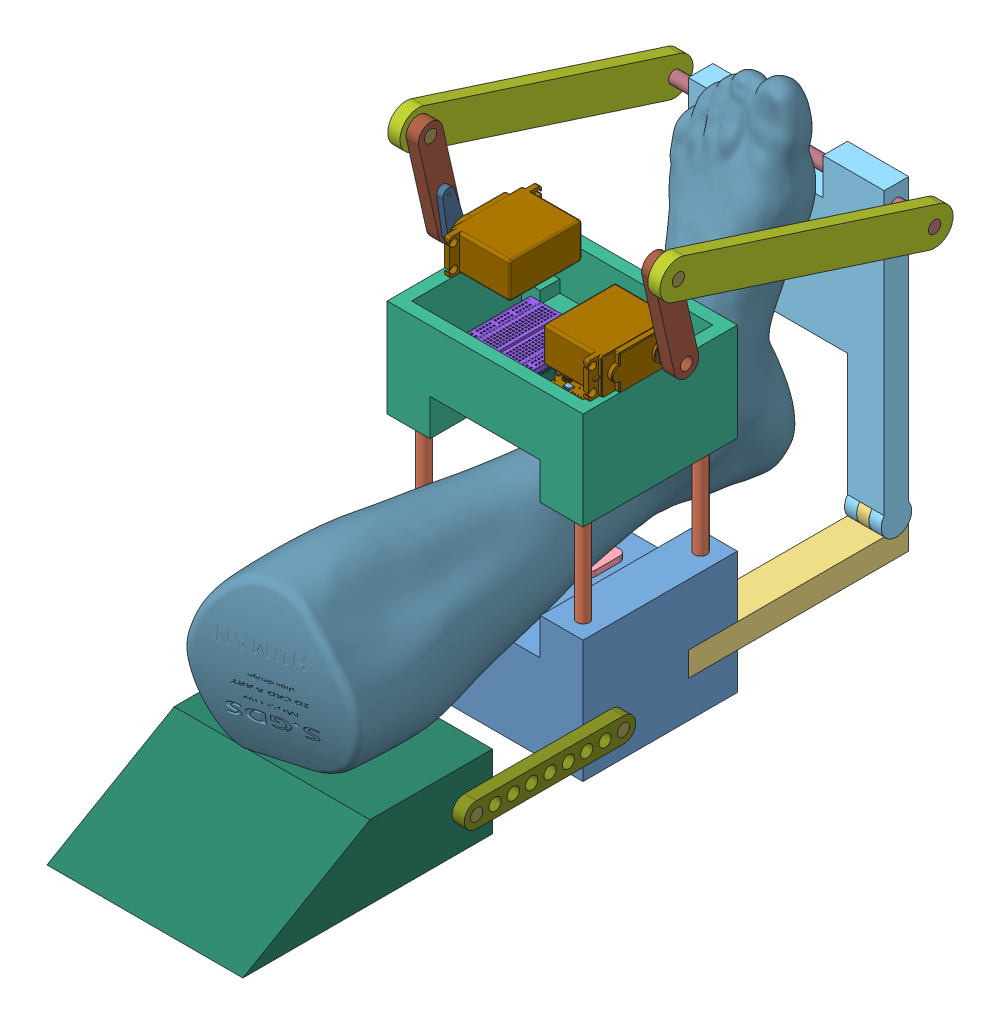
SolidWorks assembly Design104, configuration Default. Lengths in mm.
Overall size (222.4 366.53 552.81).
78 component instances, 34 part files, 73 mates.
Components (placement in the parent):
- Base-1: Base [Default] at (54.0688 54.3707 145.5855) size (160 100 126)
- AdjustmentScrew-1: AdjustmentScrew [Default] at (-10.9312 64.3707 130.5855) x (-0.217507 0 -0.976059) z (0 -1 0) size (10 10 160)
- AdjustmentScrew-2: AdjustmentScrew [Default] at (119.0688 64.3707 130.5855) x (1 0 0) z (0 -1 0) size (10 10 160)
- AdjustmentScrew-3: AdjustmentScrew [Default] at (119.0688 64.3707 34.5855) x (1 0 0) z (0 -1 0) size (10 10 160)
- AdjustmentScrew-4: AdjustmentScrew [Default] at (-10.9312 64.3707 34.5855) x (1 0 0) z (0 -1 0) size (10 10 160)
- ExtensionBase-1: ExtensionBase [Default] at (134.0688 34.3707 59.5855) size (30 40 182.5)
- ExtensionBase-2: ExtensionBase [Default] at (4.0688 34.3707 59.5855) size (30 40 182.5)
- Sensor-1: Sensor [Default] at (54.0688 78.9052 55.5855) size (20 10 30)
- Sensor-2: Sensor [Default] at (54.0688 78.1824 109.5855) size (20 10 30)
- FootBase-1: FootBase [Default] at (54.0688 184.3707 -100.4145) size (160 250 25)
- TopBox-2: TopBox [Default] at (54.0688 224.3707 145.5855) size (160 80 126)
- Connector-3: Connector [Default] at (-57.1312 318.1914 -5.7428) x (1 0 0) z (0 0.307461 0.951561) size (10 30 250)
- Connector-4: Connector [Default] at (165.2688 318.1914 -5.7428) x (-1 0 0) z (0 0.307461 0.951561) size (10 30 250)
- proto_400-2: proto_400 [Default] at (26.0688 224.3707 94.5855) x (1 0 0) z (0 1 0) size (55.3 83.3 10.01)
- Assembly Arduino Uno R3-2: Assembly Arduino Uno R3 [Default] at (52.5044 167.9903 76.8718) x (0 0 1) z (0 1 0) size (75 53.3 16.1)
  - Assembly Arduino Uno R3.STEP-1: Assembly Arduino Uno R3.STEP [Default] at origin size (75 53.3 16.1)
    - 1. Arduino uno PCB.STEP-1: 1. Arduino uno PCB.STEP [Default] at (23.1768 3.2644 56.3804) size (68.53 53.3 1.6)
    - 2. USB.STEP-1: 2. USB.STEP [Default] at (-0.091 39.0544 63.5804) x (0 -1 0) z (-1 0 0) size (14.95 14.22 16.6)
    - 12. Button arduino.STEP-1: 12. Button arduino.STEP [Default] at (-16.3125 58.8663 57.9804) size (8.4 6.2 3)
    - 3. dc jack arduino.STEP-1: 3. dc jack arduino.STEP [Default] at (-15.671 11.3644 63.4804) x (0 1 0) z (1 0 0) size (9.8 16.1 14.4)
    - 4. atmega 328p.STEP-1: 4. atmega 328p.STEP [Default] at (32.929 30.6944 58.7304) x (-1 0 0) z (0 0 -1) size (8.99 8.99 1.2)
    - 2.0  header female 6.STEP-1: 2.0  header female 6.STEP [Default] at (52.3937 64.9176 37.8614) x (0 1 0) z (1 0 0) size (2.54 11.7 15.24)
    - 2.0  header female 8.STEP-1: 2.0  header female 8.STEP [Default] at (34.6337 64.9176 37.8614) x (0 1 0) z (1 0 0) size (2.54 11.7 20.32)
    - 2.0  header female 10.STEP-1: 2.0  header female 10.STEP [Default] at (30.799 113.1576 37.8614) x (0 1 0) z (1 0 0) size (2.54 11.7 25.4)
    - 2.0  header female 8.STEP-2: 2.0  header female 8.STEP [Default] at (52.3946 113.1576 37.8614) x (0 1 0) z (1 0 0) size (2.54 11.7 20.32)
    - 5. header male.STEP-1: 5. header male.STEP [Default] at (56.3437 33.5885 57.9804) x (0 1 0) z (0 0 1) size (7.62 5.08 12.7)
    - 10. cap arduino.STEP-1: 10. cap arduino.STEP [Default] at (12.0737 13.0344 59.9804) x (-1 0 0) z (0 0 -1) size (6 5.3 6.2)
    - 10. cap arduino.STEP-2: 10. cap arduino.STEP [Default] at (4.579 13.0344 59.9804) x (-1 0 0) z (0 0 -1) size (6 5.3 6.2)
    - 8. Arduino part 16MHZ.STEP-1: 8. Arduino part 16MHZ.STEP [Default] at (14.849 43.7344 57.9804) size (13.58 4.8 3.85)
    - 8. Arduino part 16MHZ.STEP-2: 8. Arduino part 16MHZ.STEP [Default] at (41.3137 38.6244 57.9804) x (0 1 0) z (0 0 1) size (13.58 4.8 3.85)
    - 6. diode.STEP-1: 6. diode.STEP [Default] at (11.139 5.7644 59.1804) x (0 1 0) z (0 0 1) size (3.11 5.3 2.43)
    - 13. LM1117.STEP-1: 13. LM1117.STEP [Default] at (-16.299 58.867 57.8807) size (7.32 6.7 1.7)
    - 14. Micro chip part Arduino.STEP-1: 14. Micro chip part Arduino.STEP [Default] at (-16.306 58.8741 57.9804) size (9.9 6 1.75)
    - 7.Lm358 arduino.STEP-1: 7.Lm358 arduino.STEP [Default] at (17.789 18.7444 58.8704) size (6 4.9 1.75)
    - 11. Transistor.STEP-1: 11. Transistor.STEP [Default] at (-16.3121 58.8727 57.9804) size (2.34 2.92 1)
    - 11. Transistor.STEP-2: 11. Transistor.STEP [Default] at (-4.1821 48.9727 57.9804) size (2.34 2.92 1)
    - 9. part.STEP-1: 9. part.STEP [Default] at (19.109 45.7244 58.3804) x (1 0 0) z (0 1 0) size (1.05 0.4 0.55)
    - 9. part.STEP-2: 9. part.STEP [Default] at (19.109 43.3944 58.3804) x (1 0 0) z (0 1 0) size (1.05 0.4 0.55)
    - 9. part.STEP-3: 9. part.STEP [Default] at (19.109 40.6944 58.3804) x (1 0 0) z (0 1 0) size (1.05 0.4 0.55)
    - 9. part.STEP-4: 9. part.STEP [Default] at (19.109 37.9944 58.3804) x (1 0 0) z (0 1 0) size (1.05 0.4 0.55)
    - 9. part.STEP-5: 9. part.STEP [Default] at (19.109 33.0944 58.3804) x (1 0 0) z (0 1 0) size (1.05 0.4 0.55)
    - 9. part.STEP-6: 9. part.STEP [Default] at (19.109 35.4244 58.3804) x (1 0 0) z (0 1 0) size (1.05 0.4 0.55)
    - 9. part.STEP-7: 9. part.STEP [Default] at (19.109 30.4244 58.3804) x (1 0 0) z (0 1 0) size (1.05 0.4 0.55)
    - 9. part.STEP-8: 9. part.STEP [Default] at (19.109 28.1244 58.3804) x (1 0 0) z (0 1 0) size (1.05 0.4 0.55)
    - 9. part.STEP-9: 9. part.STEP [Default] at (19.109 25.7244 58.3804) x (1 0 0) z (0 1 0) size (1.05 0.4 0.55)
    - 9. part.STEP-10: 9. part.STEP [Default] at (19.109 23.4244 58.3804) x (1 0 0) z (0 1 0) size (1.05 0.4 0.55)
    - 15. part 1.STEP-1: 15. part 1.STEP [Default] at (49.8188 35.6465 58.9804) x (0 -1 0) z (1 0 0) size (2.62 1 1.38)
    - 9. part.STEP-11: 9. part.STEP [Default] at (48.0248 40.4298 57.9804) x (0 -1 0) z (-1 0 0) size (1.05 0.4 0.55)
    - 9. part.STEP-12: 9. part.STEP [Default] at (48.0248 36.0298 57.9804) x (0 -1 0) z (-1 0 0) size (1.05 0.4 0.55)
    - 9. part.STEP-13: 9. part.STEP [Default] at (48.0248 31.6298 57.9804) x (0 -1 0) z (-1 0 0) size (1.05 0.4 0.55)
    - 9. part.STEP-14: 9. part.STEP [Default] at (4.3842 45.5109 58.3804) x (1 0 0) z (0 1 0) size (1.05 0.4 0.55)
    - 9. part.STEP-15: 9. part.STEP [Default] at (8.4842 45.5109 58.3804) x (1 0 0) z (0 1 0) size (1.05 0.4 0.55)
    - 9. part.STEP-16: 9. part.STEP [Default] at (12.5842 45.5109 58.3804) x (1 0 0) z (0 1 0) size (1.05 0.4 0.55)
    - 9. part.STEP-17: 9. part.STEP [Default] at (-1.7801 31.2518 58.3804) x (1 0 0) z (0 1 0) size (1.05 0.4 0.55)
    - 9. part.STEP-18: 9. part.STEP [Default] at (-1.7801 28.9518 58.3804) x (1 0 0) z (0 1 0) size (1.05 0.4 0.55)
    - 9. part.STEP-19: 9. part.STEP [Default] at (7.5312 23.47 58.3804) x (1 0 0) z (0 1 0) size (1.05 0.4 0.55)
    - 9. part.STEP-20: 9. part.STEP [Default] at (13.1312 23.47 58.3804) x (1 0 0) z (0 1 0) size (1.05 0.4 0.55)
    - 9. part.STEP-21: 9. part.STEP [Default] at (-0.9044 25.5823 58.3804) x (0 1 0) z (-1 0 0) size (1.05 0.4 0.55)
    - 9. part.STEP-22: 9. part.STEP [Default] at (1.7956 25.5823 58.3804) x (0 1 0) z (-1 0 0) size (1.05 0.4 0.55)
    - 9. part.STEP-23: 9. part.STEP [Default] at (2.1347 17.489 58.3804) x (0 1 0) z (-1 0 0) size (1.05 0.4 0.55)
    - 9. part.STEP-24: 9. part.STEP [Default] at (9.5347 17.489 58.3804) x (0 1 0) z (-1 0 0) size (1.05 0.4 0.55)
- ServoBody-2: ServoBody [Default] at (83.0688 278.8707 97.5855) x (0 0 1) z (0 1 0) size (75 60.2 29)
- ServoBody-3: ServoBody [Default] at (25.0688 278.8707 67.0855) x (0 0 -1) z (0 1 0) size (75 60.2 29)
- ServoArm-2: ServoArm [Default] at (140.2688 278.8707 82.3355) x (0 0.221245 -0.975218) z (0 -0.975218 -0.221245) size (15 8 42.5)
- ServoArm-3: ServoArm [Default] at (-32.1312 278.8707 82.3355) x (0 -0.221245 0.975218) z (0 -0.975218 -0.221245) size (15 8 42.5)
- Link-1: Link [Default] at (145.2688 315.4414 90.6322) x (0 -0.975218 -0.221245) z (-1 0 0) size (95 20 10)
- Link-2: Link [Default] at (-47.1312 315.4414 90.6322) x (0 -0.975218 -0.221245) z (-1 0 0) size (95 20 10)
- JointRodShort-1: JointRodShort [Default] at (165.2688 352.0121 98.9288) x (0 0.751395 -0.659853) z (-1 0 0) size (10 10 20)
- JointRodShort-2: JointRodShort [Default] at (-37.1312 352.0121 98.9288) x (0 0 1) z (-1 0 0) size (10 10 20)
- JointRodLong-1: JointRodLong [Default] at (-57.1312 284.3707 -110.4145) x (0 -0.919944 -0.392049) z (1 0 0) size (10 10 222.4)
- LeftLeg-1: LeftLeg [Default] at (247.0688 269.3707 -100.4145) x (-1 0 0) z (0 1 0) size (134.54 437.6 301.13)
- KneeSupport-3: KneeSupport [Default] at (54.0688 34.3707 219.5855) size (160 60 203.92)
- AdjustmentSlot-1: AdjustmentSlot [Default] at (144.0688 34.3707 182.5855) x (0 0 1) z (-1 0 0) size (140 20 10)
- JointRodShort-3: JointRodShort [Default] at (124.0688 34.3707 122.5855) x (0 0 -1) z (1 0 0) size (10 10 20)
- JointRodShort-4: JointRodShort [Default] at (124.0688 34.3707 242.5855) x (0 0 -1) z (1 0 0) size (10 10 20)
- AdjustmentSlot-2: AdjustmentSlot [Default] at (-25.9312 34.3707 182.5855) x (0 0 1) z (-1 0 0) size (140 20 10)
- JointRodShort-5: JointRodShort [Default] at (-35.9312 34.3707 242.5855) x (0 0 -1) z (1 0 0) size (10 10 20)
- JointRodShort-6: JointRodShort [Default] at (-35.9312 34.3707 122.5855) x (0 0 -1) z (1 0 0) size (10 10 20)
Mates (geometry in assembly coordinates):
- ProfileCenter1: profile center = 0 mm anti-aligned: plane of Base-1 through (-10.9312 64.3707 130.5855) normal (0 1 0); plane of AdjustmentScrew-1 through (-10.9312 64.3707 130.5855) normal (0 -1 0)
- ProfileCenter2: profile center = 0 mm anti-aligned: plane of AdjustmentScrew-2 through (119.0688 64.3707 130.5855) normal (0 -1 0); plane of Base-1 through (119.0688 64.3707 130.5855) normal (0 1 0)
- ProfileCenter3: profile center = 0 mm anti-aligned: plane of AdjustmentScrew-3 through (119.0688 64.3707 34.5855) normal (0 -1 0); plane of Base-1 through (119.0688 64.3707 34.5855) normal (0 1 0)
- ProfileCenter4: profile center = 0 mm anti-aligned: plane of Base-1 through (-10.9312 64.3707 34.5855) normal (0 1 0); plane of AdjustmentScrew-4 through (-10.9312 64.3707 34.5855) normal (0 -1 0)
- Coincident2: coincident anti-aligned: plane of Base-1 through (54.0688 54.3707 59.5855) normal (0 0 -1); plane of ExtensionBase-1 through (104.0688 34.3707 59.5855) normal (0 0 1)
- Coincident3: coincident anti-aligned: plane of Base-1 through (104.0688 34.3707 59.5855) normal (1 0 0); plane of ExtensionBase-1 through (104.0688 34.3707 59.5855) normal (-1 0 0)
- Coincident4: coincident anti-aligned: plane of Base-1 through (134.0688 34.3707 59.5855) normal (0 1 0); plane of ExtensionBase-1 through (104.0688 34.3707 59.5855) normal (0 -1 0)
- Coincident5: coincident anti-aligned: plane of Base-1 through (54.0688 54.3707 59.5855) normal (0 0 -1); plane of ExtensionBase-2 through (-25.9312 34.3707 59.5855) normal (0 0 1)
- Coincident6: coincident anti-aligned: plane of Base-1 through (4.0688 34.3707 59.5855) normal (-1 0 0); plane of ExtensionBase-2 through (4.0688 34.3707 59.5855) normal (1 0 0)
- Coincident7: coincident anti-aligned: plane of Base-1 through (-25.9312 34.3707 59.5855) normal (0 1 0); plane of ExtensionBase-2 through (-25.9312 34.3707 59.5855) normal (0 -1 0)
- Concentric1: concentric anti-aligned: cylinder of Base-1 through (59.0688 4.3707 119.5855) axis (0 -1 0) radius 5; cylinder of Sensor-2 through (59.0688 68.1824 119.5855) axis (0 1 0) radius 5
- Coincident8: coincident anti-aligned: plane of Base-1 through (44.0688 4.3707 94.5855) normal (1 0 0); plane of Sensor-2 through (44.0688 68.1824 124.5855) normal (-1 0 0)
- Concentric2: concentric anti-aligned: cylinder of Base-1 through (59.0688 4.3707 65.5855) axis (0 -1 0) radius 5; cylinder of Sensor-1 through (59.0688 68.9052 65.5855) axis (0 1 0) radius 5
- Coincident9: coincident anti-aligned: plane of Base-1 through (44.0688 4.3707 70.5855) normal (1 0 0); plane of Sensor-1 through (44.0688 68.9052 70.5855) normal (-1 0 0)
- Concentric3: concentric anti-aligned: cylinder of ExtensionBase-1 through (124.0688 61.8707 -110.4145) axis (-1 0 0) radius 12.5; cylinder of FootBase-1 through (124.0688 61.8707 -110.4145) axis (1 0 0) radius 12.5
- Coincident10: coincident anti-aligned: plane of ExtensionBase-2 through (-5.9312 61.8707 -110.4145) normal (1 0 0); plane of FootBase-1 through (-5.9312 61.8707 -110.4145) normal (-1 0 0)
- LimitAngle1: limit planar angle = 1.570796 rad anti-aligned: plane of ExtensionBase-1 through (134.0688 34.3707 59.5855) normal (0 1 0); plane of FootBase-1 through (54.0688 184.3707 -100.4145) normal (0 0 1)
- ProfileCenter7: profile center = 0 mm aligned: plane of AdjustmentScrew-2 through (119.0688 224.3707 130.5855) normal (0 1 0); plane of TopBox-2 through (119.0688 224.3707 130.5855) normal (0 -1 0)
- Coincident25: coincident anti-aligned: plane of TopBox-2 through (9.0688 224.3707 19.5855) normal (0 1 0); plane of proto_400-2 through (26.0688 224.3707 94.5855) normal (0 -1 0)
- Coincident26: coincident anti-aligned: plane of TopBox-2 through (54.0688 224.3707 135.5855) normal (0 0 -1); plane of proto_400-2 through (-0.9312 234.3707 135.5855) normal (0 0 1)
- Coincident31: coincident anti-aligned: plane of TopBox-2 through (54.0688 224.3707 135.5855) normal (0 0 -1); plane of Assembly Arduino Uno R3-2/Assembly Arduino Uno R3.STEP-1/1. Arduino uno PCB.STEP-1 through (60.847 225.9707 135.5855) normal (0 0 1)
- Coincident30: coincident anti-aligned: plane of TopBox-2 through (9.0688 224.3707 19.5855) normal (0 1 0); plane of Assembly Arduino Uno R3-2/Assembly Arduino Uno R3.STEP-1/1. Arduino uno PCB.STEP-1 through (55.7688 224.3707 100.0486) normal (0 -1 0)
- Coincident32: coincident anti-aligned: plane of TopBox-2 through (-0.9312 234.3707 135.5855) normal (1 0 0); plane of proto_400-2 through (-0.9312 234.3707 53.5855) normal (-1 0 0)
- Coincident33: coincident anti-aligned: plane of TopBox-2 through (109.0688 234.3707 135.5855) normal (-1 0 0); plane of Assembly Arduino Uno R3-2/Assembly Arduino Uno R3.STEP-1/1. Arduino uno PCB.STEP-1 through (109.0688 225.9707 131.5229) normal (1 0 0)
- Coincident39: coincident anti-aligned: plane of TopBox-2 through (-25.9312 264.3707 19.5855) normal (0 1 0); plane of ServoBody-2 through (130.0688 264.3707 68.0855) normal (0 -1 0)
- Coincident40: coincident aligned: plane of ServoBody-2 through (124.0688 293.3707 60.0855) normal (-1 0 0); plane of TopBox-2 through (124.0688 184.3707 19.5855) normal (-1 0 0)
- Coincident41: coincident anti-aligned: plane of TopBox-2 through (-25.9312 264.3707 19.5855) normal (0 1 0); plane of ServoBody-3 through (-21.9312 264.3707 96.5855) normal (0 -1 0)
- Coincident42: coincident aligned: plane of ServoBody-3 through (-15.9312 293.3707 104.5855) normal (1 0 0); plane of TopBox-2 through (-15.9312 184.3707 19.5855) normal (1 0 0)
- Concentric10: concentric anti-aligned: cylinder of ServoBody-2 through (143.2688 278.8707 82.3355) axis (-1 0 0) radius 4; cylinder of ServoBody-3 through (-35.1312 278.8707 82.3355) axis (1 0 0) radius 4
- Coincident44: coincident anti-aligned: plane of TopBox-2 through (54.0688 224.3707 29.5855) normal (0 0 1); plane of ServoBody-3 through (25.0688 278.8707 29.5855) normal (0 0 -1)
- Concentric11: concentric anti-aligned: cylinder of ServoBody-2 through (143.2688 278.8707 82.3355) axis (-1 0 0) radius 4; cylinder of ServoArm-2 through (140.2688 278.8707 82.3355) axis (1 0 0) radius 4
- Coincident45: coincident anti-aligned: plane of ServoBody-2 through (143.2688 278.8707 82.3355) normal (1 0 0); circle of ServoArm-2
- Concentric12: concentric anti-aligned: cylinder of ServoBody-3 through (-35.1312 278.8707 82.3355) axis (1 0 0) radius 4; cylinder of ServoArm-3 through (-32.1312 278.8707 82.3355) axis (-1 0 0) radius 4
- Coincident46: coincident anti-aligned: plane of ServoBody-3 through (-35.1312 278.8707 82.3355) normal (-1 0 0); plane of ServoArm-3 through (-35.1312 278.8707 82.3355) normal (1 0 0)
- Coincident47: coincident aligned: plane of ServoArm-2 through (145.2688 277.2114 89.6496) normal (0 -0.139493 0.990223); plane of ServoArm-3 through (-37.1312 307.0211 93.8489) normal (0 -0.139493 0.990223)
- LimitAngle3: limit planar angle = 1.347706 rad aligned: plane of ServoArm-2 through (140.2688 278.8707 82.3355) normal (0 0.221245 -0.975218); plane of ServoBody-2 through (83.0688 278.8707 97.5855) normal (0 1 0)
- Concentric14: concentric anti-aligned: cylinder of ServoBody-2 through (139.2688 278.8707 82.3355) axis (1 0 0) radius 2; cylinder of Link-1 through (155.2688 278.8707 82.3355) axis (-1 0 0) radius 5
- Coincident49: coincident anti-aligned: plane of ServoArm-2 through (145.2688 278.8707 82.3355) normal (1 0 0); plane of Link-1 through (145.2688 352.0121 98.9288) normal (-1 0 0)
- Coincident50: coincident anti-aligned: plane of ServoArm-2 through (140.2688 278.8707 82.3355) normal (0 0.221245 -0.975218); plane of Link-1 through (145.2688 315.4414 90.6322) normal (0 -0.221245 0.975218)
- Concentric15: concentric anti-aligned: line of ServoArm-3 through (-37.1312 278.8707 82.3355) axis (1 0 0); cylinder of Link-2 through (-37.1312 278.8707 82.3355) axis (-1 0 0) radius 5
- Coincident51: coincident anti-aligned: plane of ServoArm-3 through (-37.1312 278.8707 82.3355) normal (-1 0 0); plane of Link-2 through (-37.1312 352.0121 98.9288) normal (1 0 0)
- Coincident52: coincident aligned: plane of ServoArm-3 through (-32.1312 278.8707 82.3355) normal (0 -0.221245 0.975218); plane of Link-2 through (-47.1312 315.4414 90.6322) normal (0 -0.221245 0.975218)
- Concentric16: concentric anti-aligned: cylinder of Link-2 through (-37.1312 352.0121 98.9288) axis (-1 0 0) radius 5; cylinder of JointRodShort-2 through (-57.1312 352.0121 98.9288) axis (1 0 0) radius 5
- Concentric18: concentric anti-aligned: cylinder of Link-1 through (155.2688 352.0121 98.9288) axis (-1 0 0) radius 5; cylinder of JointRodShort-1 through (145.2688 352.0121 98.9288) axis (1 0 0) radius 5
- Concentric19: concentric aligned: cylinder of Connector-4 through (155.2678 352.0121 98.9288) axis (1 0 0) radius 5; cylinder of JointRodShort-1 through (145.2688 352.0121 98.9288) axis (1 0 0) radius 5
- Coincident57: coincident aligned: plane of Link-2 through (-37.1312 352.0121 98.9288) normal (1 0 0); plane of JointRodShort-2 through (-37.1312 352.0121 98.9288) normal (1 0 0)
- Coincident58: coincident aligned: plane of Connector-3 through (-57.1312 352.0121 98.9288) normal (-1 0 0); plane of JointRodShort-2 through (-57.1312 352.0121 98.9288) normal (-1 0 0)
- Coincident59: coincident aligned: plane of Connector-4 through (165.2688 352.0121 98.9288) normal (1 0 0); plane of JointRodShort-1 through (165.2688 352.0121 98.9288) normal (1 0 0)
- Coincident60: coincident aligned: plane of Link-1 through (145.2688 352.0121 98.9288) normal (-1 0 0); plane of JointRodShort-1 through (145.2688 352.0121 98.9288) normal (-1 0 0)
- Concentric20: concentric anti-aligned: cylinder of JointRodLong-1 through (165.2688 284.3707 -110.4145) axis (-1 0 0) radius 5; cylinder of FootBase-1 through (-25.9322 284.3707 -110.4145) axis (1 0 0) radius 5
- Coincident61: coincident aligned: plane of Connector-4 through (165.2688 352.0121 98.9288) normal (1 0 0); plane of JointRodLong-1 through (165.2688 284.3707 -110.4145) normal (1 0 0)
- Concentric25: concentric anti-aligned: cylinder of Connector-4 through (155.2678 284.3707 -110.4145) axis (1 0 0) radius 5; cylinder of JointRodLong-1 through (165.2688 284.3707 -110.4145) axis (-1 0 0) radius 5
- Concentric28: concentric anti-aligned: cylinder of Connector-3 through (-47.1302 352.0121 98.9288) axis (-1 0 0) radius 5; cylinder of JointRodShort-2 through (-57.1312 352.0121 98.9288) axis (1 0 0) radius 5
- Concentric30: concentric aligned: cylinder of Connector-3 through (-47.1302 284.3707 -110.4145) axis (-1 0 0) radius 5; cylinder of JointRodLong-1 through (165.2688 284.3707 -110.4145) axis (-1 0 0) radius 5
- Distance1: distance = 113 mm anti-aligned: plane of LeftLeg-1 through (247.0688 269.3707 -100.4145) normal (-1 0 0); plane of Base-1 through (134.0688 4.3707 19.5855) normal (1 0 0)
- Coincident64: coincident aligned: plane of FootBase-1 through (54.0688 184.3707 -100.4145) normal (0 0 1); plane of LeftLeg-1 through (247.0688 269.3707 -100.4145) normal (0 0 1)
- Distance2: distance = 55 mm anti-aligned: plane of LeftLeg-1 through (247.0688 269.3707 -100.4145) normal (0 1 0); plane of TopBox-2 through (9.0688 214.3707 19.5855) normal (0 -1 0)
- Parallel2: parallel anti-aligned: plane of Base-1 through (54.0688 54.3707 145.5855) normal (0 0 1); plane of KneeSupport-3 through (54.0688 34.3707 219.5855) normal (0 0 -1)
- Coincident66: coincident aligned: plane of Base-1 through (134.0688 4.3707 19.5855) normal (1 0 0); plane of KneeSupport-3 through (134.0688 4.3707 449.5855) normal (1 0 0)
- Coincident67: coincident aligned: plane of Base-1 through (-25.9312 4.3707 19.5855) normal (0 -1 0); plane of KneeSupport-3 through (-25.9312 4.3707 449.5855) normal (0 -1 0)
- Coincident68: coincident anti-aligned: plane of KneeSupport-3 through (134.0688 4.3707 449.5855) normal (1 0 0); plane of AdjustmentSlot-1 through (134.0688 34.3707 122.5855) normal (-1 0 0)
- Concentric31: concentric anti-aligned: cylinder of AdjustmentSlot-1 through (134.0688 34.3707 242.5855) axis (1 0 0) radius 5; cylinder of JointRodShort-4 through (144.0688 34.3707 242.5855) axis (-1 0 0) radius 5
- Coincident69: coincident aligned: plane of AdjustmentSlot-1 through (144.0688 34.3707 122.5855) normal (1 0 0); plane of JointRodShort-4 through (144.0688 34.3707 242.5855) normal (1 0 0)
- Concentric32: concentric anti-aligned: cylinder of AdjustmentSlot-1 through (134.0688 34.3707 122.5855) axis (1 0 0) radius 5; cylinder of JointRodShort-3 through (144.0688 34.3707 122.5855) axis (-1 0 0) radius 5
- Coincident70: coincident aligned: plane of AdjustmentSlot-1 through (144.0688 34.3707 122.5855) normal (1 0 0); plane of JointRodShort-3 through (144.0688 34.3707 122.5855) normal (1 0 0)
- Concentric33: concentric anti-aligned: cylinder of Base-1 through (-25.9312 34.3707 122.5855) axis (1 0 0) radius 5; cylinder of JointRodShort-3 through (144.0688 34.3707 122.5855) axis (-1 0 0) radius 5
- Concentric34: concentric anti-aligned: cylinder of KneeSupport-3 through (-25.9312 34.3707 242.5855) axis (1 0 0) radius 5; cylinder of JointRodShort-4 through (144.0688 34.3707 242.5855) axis (-1 0 0) radius 5
- Coincident71: coincident anti-aligned: plane of KneeSupport-3 through (-25.9312 4.3707 449.5855) normal (-1 0 0); plane of AdjustmentSlot-2 through (-25.9312 34.3707 122.5855) normal (1 0 0)
- Concentric35: concentric anti-aligned: cylinder of AdjustmentSlot-2 through (-35.9312 34.3707 122.5855) axis (1 0 0) radius 5; cylinder of JointRodShort-6 through (-15.9312 34.3707 122.5855) axis (-1 0 0) radius 5
- Coincident72: coincident aligned: plane of AdjustmentSlot-2 through (-35.9312 34.3707 122.5855) normal (-1 0 0); plane of JointRodShort-6 through (-35.9312 34.3707 122.5855) normal (-1 0 0)
- Concentric36: concentric anti-aligned: cylinder of AdjustmentSlot-2 through (-35.9312 34.3707 242.5855) axis (1 0 0) radius 5; cylinder of JointRodShort-5 through (-15.9312 34.3707 242.5855) axis (-1 0 0) radius 5
- Coincident73: coincident aligned: plane of AdjustmentSlot-2 through (-35.9312 34.3707 122.5855) normal (-1 0 0); plane of JointRodShort-5 through (-35.9312 34.3707 242.5855) normal (-1 0 0)
- Concentric37: concentric anti-aligned: cylinder of Base-1 through (-25.9312 34.3707 122.5855) axis (1 0 0) radius 5; cylinder of JointRodShort-6 through (-15.9312 34.3707 122.5855) axis (-1 0 0) radius 5
